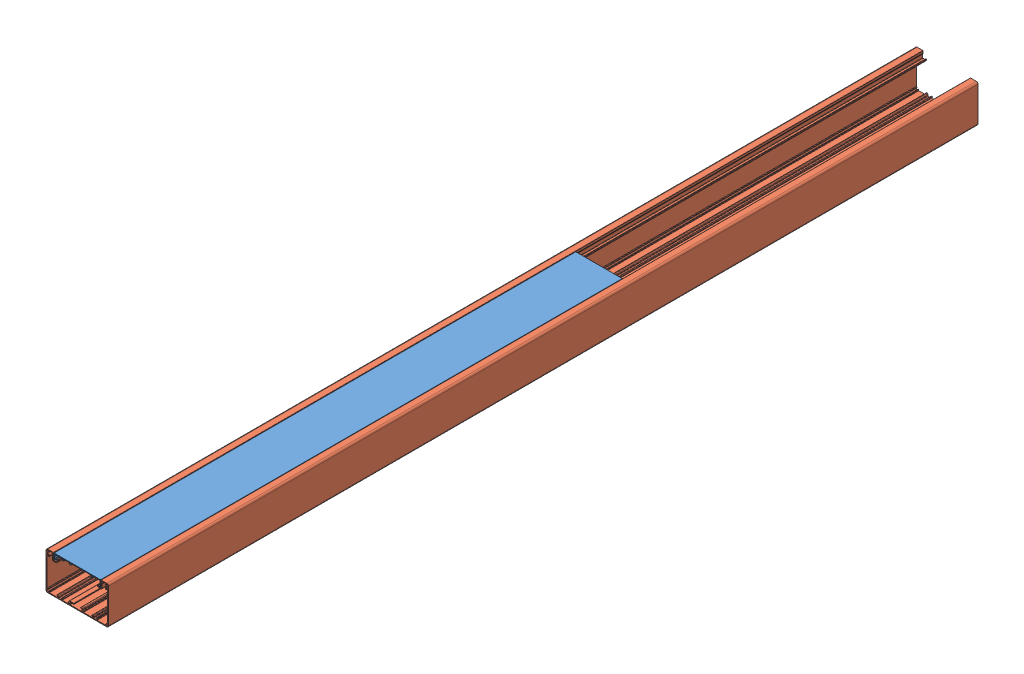
SolidWorks assembly Сборка1, configuration По умолчанию. Lengths in mm.
Overall size (107.8 65 1500).
2 component instances, 2 part files, 1 mates.
Components (placement in the parent):
- AL-214445 копия крышка-1: AL-214445 копия крышка [00] at (5.3362 39.7872 2.7833) size (81.96 11.18 900)
- AL-232600-1: AL-232600 [-01] at (2.3233 4.8001 802.7833) size (107.8 65 1500)
Mates (geometry in assembly coordinates):
- Совпадение1: coincident aligned: plane of AL-214445 копия крышка-1 through (44.8029 66.2726 902.7833) normal (0 0 1); plane of AL-232600-1 through (30.2233 7.3782 902.7833) normal (0 0 1)
